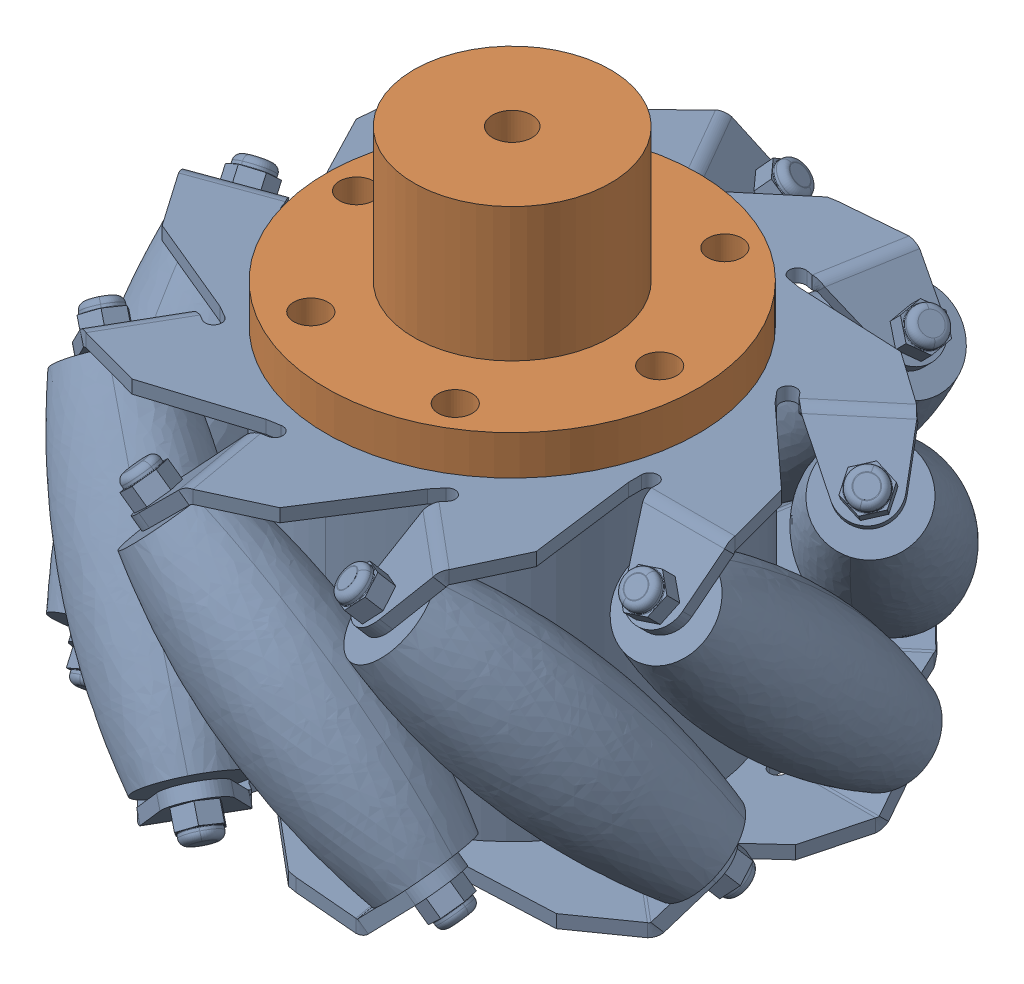
SolidWorks assembly 100mm_RB, configuration 默认. Lengths in mm.
Overall size (102.05 76.39 102.38).
2 component instances, 2 part files, 4 mates.
Components (placement in the parent):
- 100mm_RB-1: 100mm_RB [默认] at (0.8617 -18.6188 0.6074) size (102.05 50.01 102.38)
- 6mm_TightCoupling-2: 6mm_TightCoupling [默认] at (0.8617 29.2925 0.6074) x (0.5 0 0.866025) z (0 1 0) size (56.8 56.8 26.4)
Mates (geometry in assembly coordinates):
- 同心6: concentric: cylinder of 100mm_RB-1 through (12.7367 29.2925 -19.9607) axis (0 -1 0) radius 2.5; cylinder of 6mm_TightCoupling-2 through (12.7367 29.2925 -19.9607) axis (0 1 0) radius 2.6
- 同心7: concentric: cylinder of 100mm_RB-1 through (12.7367 29.2925 21.1755) axis (0 -1 0) radius 2.5; cylinder of 6mm_TightCoupling-2 through (12.7367 29.2925 21.1755) axis (0 1 0) radius 2.6
- 同心8: concentric: cylinder of 100mm_RB-1 through (-22.8883 29.2925 0.6074) axis (0 -1 0) radius 2.5; cylinder of 6mm_TightCoupling-2 through (-22.8883 29.2925 0.6074) axis (0 1 0) radius 2.6
- 重合1: coincident anti-aligned: plane of 100mm_RB-1 through (0.8617 29.2925 0.6074) normal (0 1 0); plane of 6mm_TightCoupling-2 through (-2.9432 29.2925 -5.9828) normal (0 -1 0)
